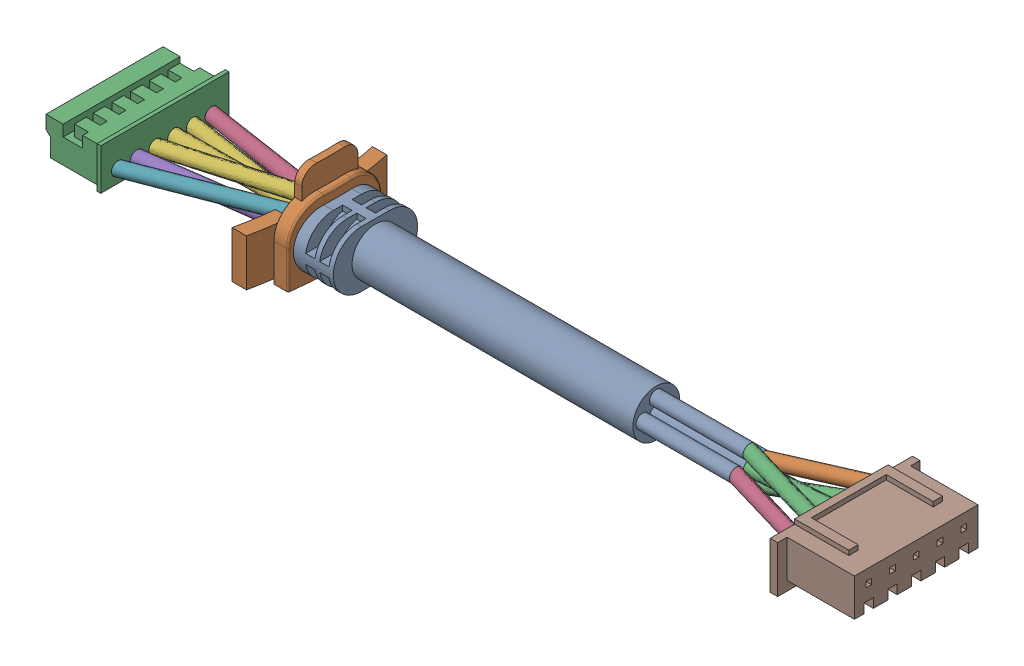
SolidWorks assembly Íâ½ÓÏßÕûÌå, configuration Défaut. Lengths in mm.
Overall size (86.12 10.5 15.7).
6 component instances, 6 part files, 0 mates.
Components (placement in the parent):
- 4pinÏßÀÂ-1: 4pinÏßÀÂ [Défaut] at (-33.3982 25.5643 0) size (47.5 6 9)
- ½ÓÏß¶Ë¸Ç-1: ½ÓÏß¶Ë¸Ç [Défaut] at (-69.3982 22.0643 0) x (0 0 1) z (-1 0 0) size (15 10.5 3.83)
- 6p ²åÍ·-1: 6p ²åÍ· [Défaut] at (-51.3982 24.9643 0) x (0 0 1) z (-1 0 0) size (13.7 5 6.45)
- Áã¼þ4^Íâ½ÓÏßÕûÌå-1: Áã¼þ4^Íâ½ÓÏßÕûÌå [Défaut] at (-35.3982 25.5643 0) x (0 0 1) z (-1 0 0) size (11.49 4.16 15)
- 5pin 2.54²åÍ·-1: 5pin 2.54²åÍ· [Défaut] at (22.0731 25.0643 -0.6) x (1 0 0) z (0 0 -1) size (8 5.5 15.2)
- Áã¼þ1^Íâ½ÓÏßÕûÌå-1: Áã¼þ1^Íâ½ÓÏßÕûÌå [Défaut] at (22.0731 25.0643 -0.6) x (0 0 -1) z (-1 0 0) size (11.69 4.45 9.97)
